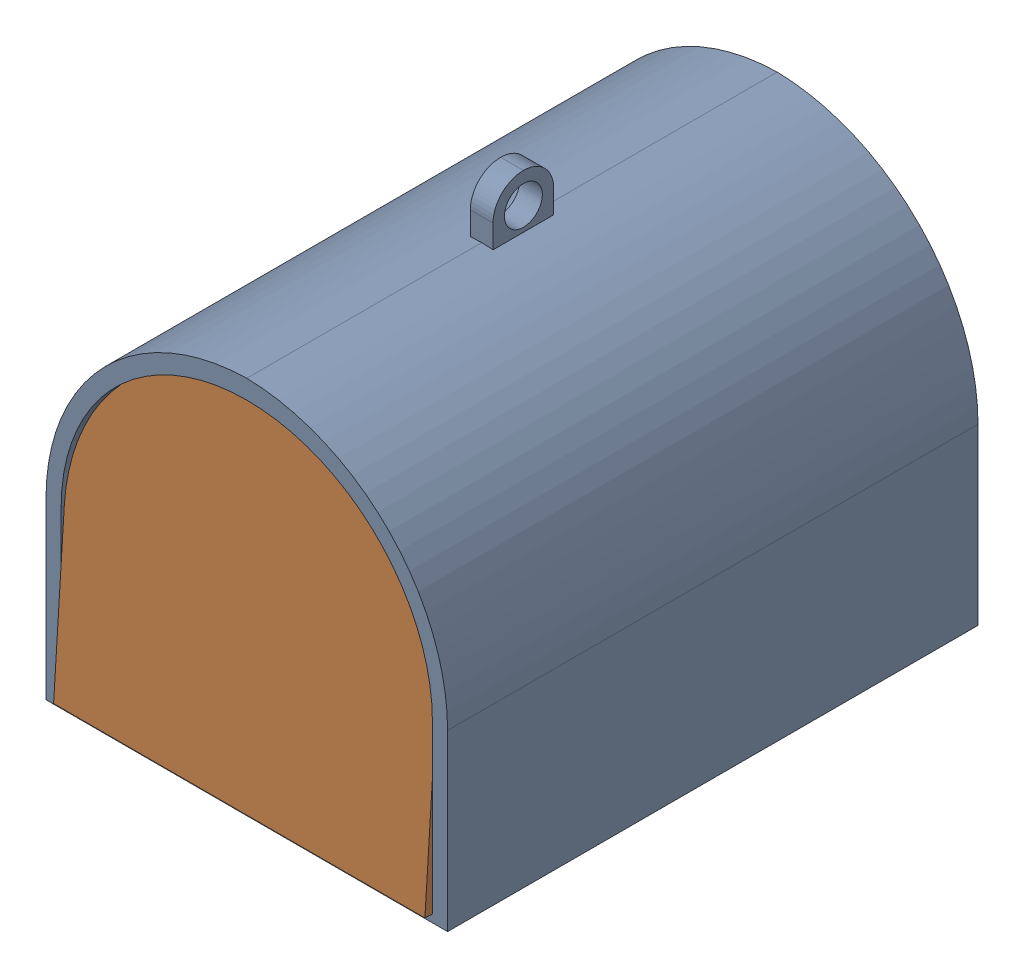
SolidWorks assembly box assembly, configuration Défaut. Lengths in mm.
Overall size (53 57 71).
2 component instances, 2 part files, 2 mates.
Components (placement in the parent):
- box-1: box [Défaut] at origin size (53 57 70)
- port-1: port [Défaut] at (2 1 70) x (1 0 0) z (0 0.064323 0.997929) size (49 46.5 1)
Mates (geometry in assembly coordinates):
- Coïncidente1: coincident aligned: line of box-1 through (2 1 70) axis (1 0 0); line of port-1 through (2 1 70) axis (1 0 0)
- Coïncidente3: coincident: point of box-1; point of port-1
